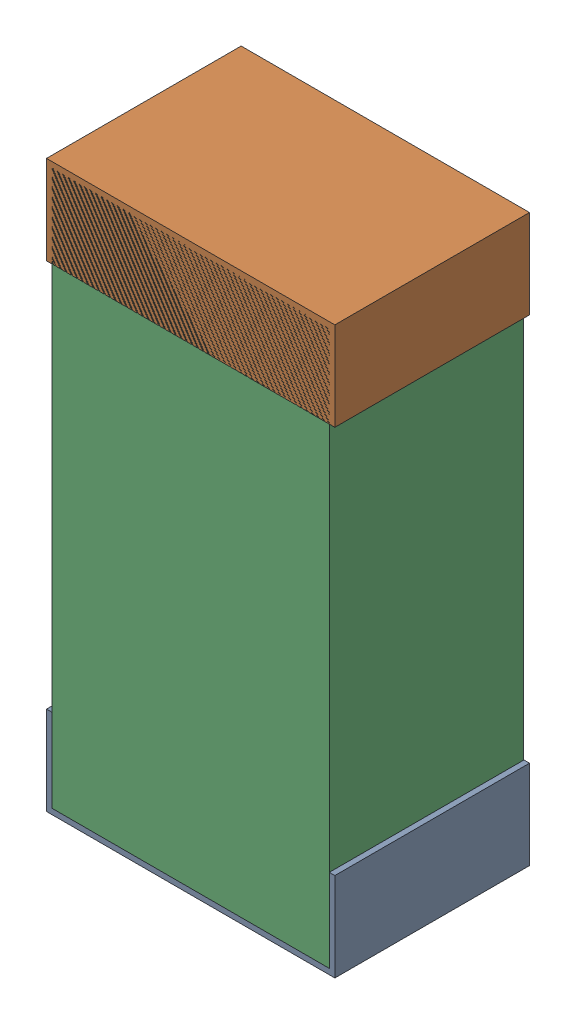
SolidWorks assembly C21, configuration Default. Lengths in mm.
Overall size (0.52 1.02 0.35).
6 component instances, 2 part files, 0 mates.
Components (placement in the parent):
- 870941120-1: 870941120 [Default] at (8.636 41.099 -1.9516) size (0.52 0.16 0.35)
  - Extruded_3-1: Extruded_3 [Default] at origin size (0.52 0.16 0.35)
- 870941120-2: 870941120 [Default] at (8.636 41.959 -1.9516) size (0.52 0.16 0.35)
  - Extruded_3-1: Extruded_3 [Default] at origin size (0.52 0.16 0.35)
- 870941280-1: 870941280 [Default] at (8.636 41.529 -1.9506) size (0.5 1 0.35)
  - Extruded_4-1: Extruded_4 [Default] at origin size (0.5 1 0.35)
